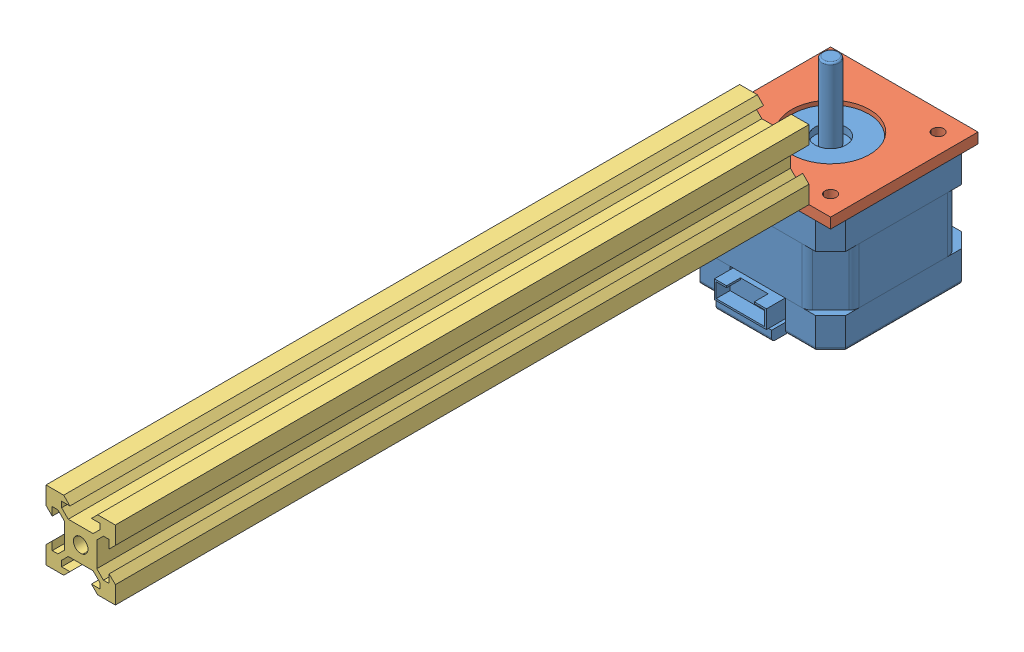
SolidWorks assembly Y_motor_mount, configuration Default. Lengths in mm.
Overall size (42.5 56.15 242.5).
3 component instances, 3 part files, 5 mates.
Components (placement in the parent):
- Nema_17-1: Nema_17 [Default] at (33.488 30.381 30.4531) size (42 55.32 47)
- Y_motor_mount-1: Y_motor_mount [Default] at (33.488 38.381 30.4531) size (42.5 3 42.5)
- 200mm_20x20-1: 200mm_20x20 [Default] at (38.503 51.381 151.7031) size (20 20 200)
Mates (geometry in assembly coordinates):
- Coincident1: coincident anti-aligned: plane of Nema_17-1 through (33.488 38.381 30.4531) normal (0 1 0); plane of Y_motor_mount-1 through (33.488 38.381 30.4531) normal (0 -1 0)
- Concentric2: concentric aligned: circle of Nema_17-1; circle of Y_motor_mount-1
- Concentric3: concentric aligned: circle of Nema_17-1; circle of Y_motor_mount-1
- Coincident2: coincident: plane of Y_motor_mount-1 through (12.238 41.381 51.7031) normal (0 0 1); plane of 200mm_20x20-1 through (38.503 51.381 51.7031) normal (0 0 -1)
- Coincident3: coincident anti-aligned: plane of Y_motor_mount-1 through (33.488 41.381 30.4531) normal (0 1 0); plane of 200mm_20x20-1 through (28.503 41.381 251.7031) normal (0 -1 0)
